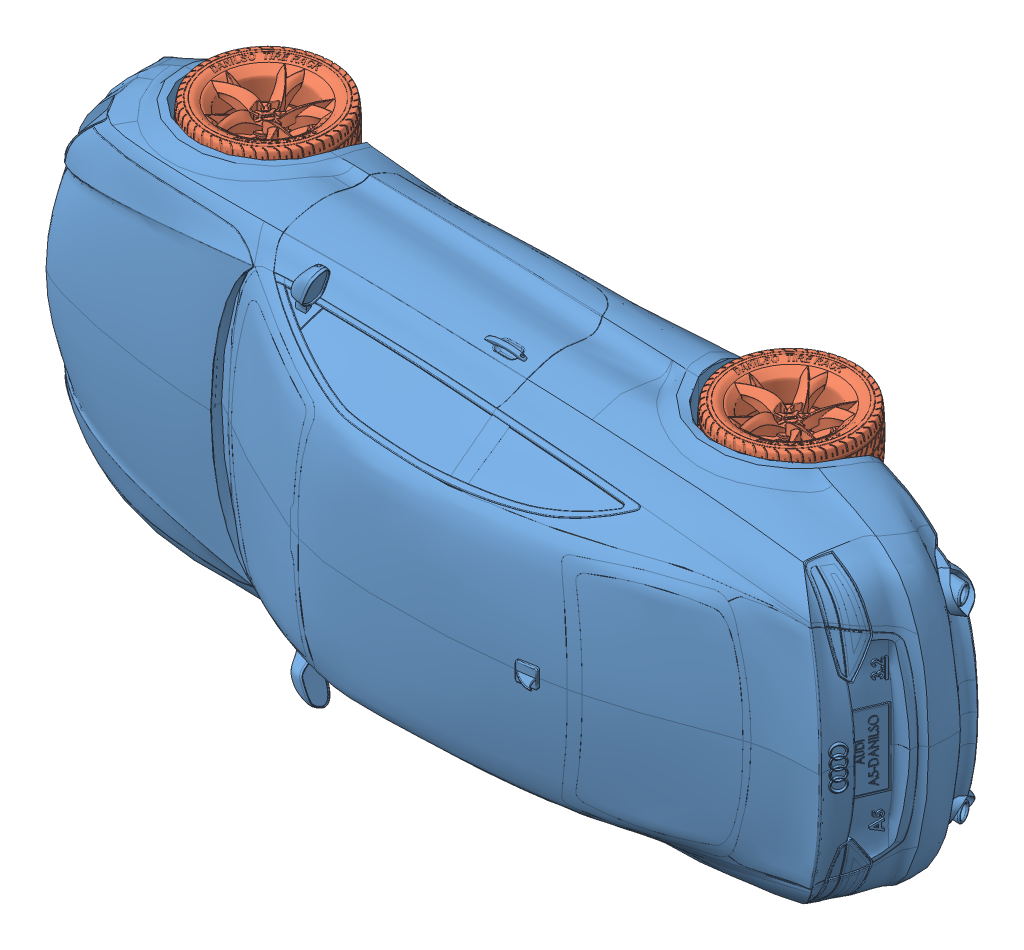
SolidWorks assembly a52, configuration 預設. Lengths in mm.
Overall size (4720.88 2024.74 1631.72).
9 component instances, 3 part files, 12 mates.
Components (placement in the parent):
- audia54-1: audia54 [預設] at origin size (4720.88 2024.74 1560.54)
- auto輪bigxt-1: auto輪bigxt [預設] at (-1450 -840 330) x (0 0 1) z (0 -1 0) size (707.8 707.8 302.35)
- auto輪bigxt-2: auto輪bigxt [預設] at (1300 -840 330) x (0 0 1) z (0 -1 0) size (707.8 707.8 302.35)
- auto輪bigxt-5: auto輪bigxt [預設] at (1300 840 330) x (-0.546944 0 0.837169) z (0 1 0) size (707.8 707.8 302.35)
- auto輪bigxt-4: auto輪bigxt [預設] at (-1450 840 330) x (-0.546944 0 0.837169) z (0 1 0) size (707.8 707.8 302.35)
- 汽车椅-1: 汽车椅 [Default] at (0 -400 250) x (0 -1 0) z (0 0 1) size (612.08 799.61 954.28)
- 汽车椅-2: 汽车椅 [Default] at (0 400 250) x (0 -1 0) z (0 0 1) size (612.08 799.61 954.28)
- 汽车椅-4: 汽车椅 [Default] at (800 -400 250) x (0 -1 0) z (0 0 1) size (612.08 799.61 954.28)
- 汽车椅-3: 汽车椅 [Default] at (800 400 250) x (0 -1 0) z (0 0 1) size (612.08 799.61 954.28)
Mates (geometry in assembly coordinates):
- 平行相距1: distance = 840 mm anti-aligned: plane of auto輪bigxt-1 through (-1450 -840 330) normal (0 -1 0); plane of assembly through (0 0 0) normal (0 1 0)
- 平行相距2: distance = 1450 mm anti-aligned: plane of audia54-1 through (0 0 0) normal (1 0 0); plane of auto輪bigxt-1
- 平行相距3: distance = 330 mm aligned: plane of auto輪bigxt-1; plane of audia54-1 through (0 0 0) normal (0 0 1)
- 平行相距4: distance = 1300 mm anti-aligned: plane of auto輪bigxt-2; plane of assembly through (0 0 0) normal (1 0 0)
- 平行相距5: distance = 840 mm aligned: plane of auto輪bigxt-4 through (-1450 840 330) normal (0 1 0); plane of audia54-1 through (0 0 0) normal (0 1 0)
- 平行相距6: distance = 840 mm aligned: plane of auto輪bigxt-5 through (1300 840 330) normal (0 1 0); plane of assembly through (0 0 0) normal (0 1 0)
- 平行相距7: distance = 250 mm aligned: plane of 汽车椅-1 through (0 -400 250) normal (0 0 1); plane of audia54-1 through (0 0 0) normal (0 0 1)
- 重合/共線/共點5: coincident aligned: plane of audia54-1 through (0 0 0) normal (1 0 0); plane of 汽车椅-1
- 重合/共線/共點6: coincident anti-aligned: plane of audia54-1 through (0 -400 0) normal (0 1 0); plane of 汽车椅-1
- 平行相距8: distance = 400 mm anti-aligned: plane of 汽车椅-2; plane of audia54-1 through (0 0 0) normal (0 1 0)
- 重合/共線/共點8: coincident aligned: plane of 汽车椅-4; plane of 汽车椅-3
- 平行相距9: distance = 800 mm aligned: plane of 汽车椅-3; plane of audia54-1 through (0 0 0) normal (1 0 0)
